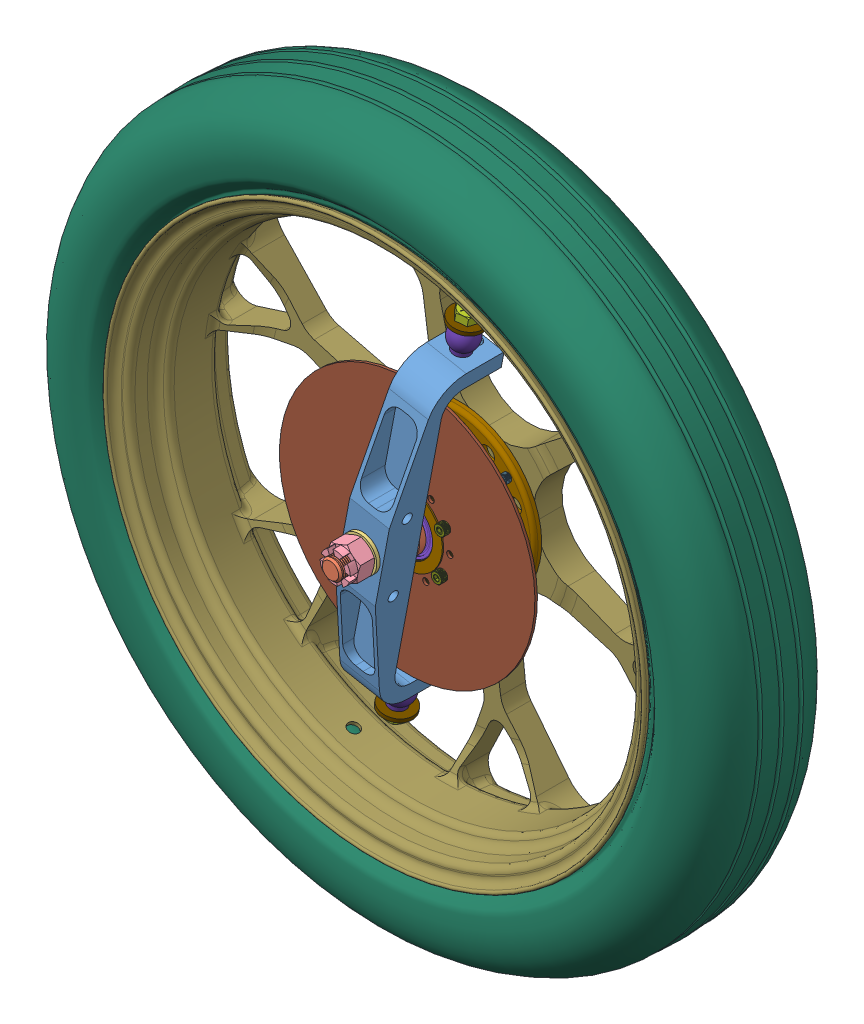
SolidWorks assembly SpindleAssy, configuration Default. Lengths in mm.
Overall size (616.2 616.2 50000).
36 component instances, 18 part files, 73 mates.
Components (placement in the parent):
- Knuckle-1: Knuckle [Default] at (82.0121 130.0239 204.0915) size (78.12 253.33 73.5)
- Spindle_Light-1: Spindle_Light [Default] at (82.0121 130.0239 204.0915) x (0 0 -1) z (0.185408 0.982662 0) size (50000 34 30)
- M16 98688A121_General Purpose Zinc-Plated Steel Washer-1: M16 98688A121_General Purpose Zinc-Plated Steel Washer [98688A121] at (82.0121 130.0239 232.5915) x (0.99983 -0.018445 0) z (0 0 1) size (28 28 2.7)
- M16x1-5 93760A128_Steel Locknut for Use with Cotter Pins-1: M16x1-5 93760A128_Steel Locknut for Use with Cotter Pins [93760A128] at (82.0121 130.0239 254.2915) x (0.982886 -0.184217 0) z (0 0 1) size (24 27.71 19.76)
- M14 98689A119_General Purpose 18-8 Stainless Steel Washer-1: M14 98689A119_General Purpose 18-8 Stainless Steel Washer [98689A119] at (82.0121 130.0239 138.2415) size (24 24 2.7)
- M14x1-5 93760A127_Steel Locknut for Use with Cotter Pins-1: M14x1-5 93760A127_Steel Locknut for Use with Cotter Pins [93760A127] at (82.0121 130.0239 120.8915) x (-0.661913 -0.74958 0) z (0 0 -1) size (22 25.4 16.76)
- 91257A659_Zinc Yellow-Chromate Plated Hex Head Screw-2: 91257A659_Zinc Yellow-Chromate Plated Hex Head Screw [91257A659] at (58.1191 3.3909 177.4439) x (0.185408 0.982662 0) z (0.110595 -0.020867 0.993646) size (57.6 16.5 14.29)
- 91257A659_Zinc Yellow-Chromate Plated Hex Head Screw-3: 91257A659_Zinc Yellow-Chromate Plated Hex Head Screw [91257A659] at (105.9051 256.6568 177.4439) x (-0.185408 -0.982662 0) z (-0.685297 0.129301 0.716693) size (57.6 16.5 14.29)
- SKF_6004-2Z.stp-1: SKF_6004-2Z.stp [Default] at (82.0121 130.0239 185.0915) x (0 0 1) z (-0.58163 0.813454 0) size (12 42 42)
- Hub5-16-1: Hub5-16 [Default] at (82.0121 130.0239 173.6746) x (-0.944813 0.32761 0) z (0.32761 0.944813 0) size (130 85 130)
- SKF_6003-2Z.stp-1: SKF_6003-2Z.stp [Default] at (82.0121 130.0239 149.5915) x (0 0 -1) z (0.973183 -0.230032 0) size (10 35 35)
- BasicBrakeDisc-1: BasicBrakeDisc [Default] at (82.0121 130.0239 195.0915) x (0.071911 0.997411 0) z (0 0 1) size (190.5 190.5 3.17)
- rimmachined v13.2-1: rimmachined v13.2 [Default] at (82.0121 130.0239 177.3915) x (0 0 -1) z (-0.981935 -0.189217 0) size (93.59 431.57 431.57)
- 92415A381_Zinc-Plated Steel Unthreaded Spacer-2: 92415A381_Zinc-Plated Steel Unthreaded Spacer [92415A381] at (71.0682 186.982 155.2387) size (7.94 7.94 7.21)
- 92415A381_Zinc-Plated Steel Unthreaded Spacer-3: 92415A381_Zinc-Plated Steel Unthreaded Spacer [92415A381] at (27.2129 149.0252 155.2387) size (7.94 7.94 7.21)
- 92415A381_Zinc-Plated Steel Unthreaded Spacer-4: 92415A381_Zinc-Plated Steel Unthreaded Spacer [92415A381] at (38.1569 92.0671 155.2387) size (7.94 7.94 7.21)
- 92415A381_Zinc-Plated Steel Unthreaded Spacer-5: 92415A381_Zinc-Plated Steel Unthreaded Spacer [92415A381] at (92.956 73.0657 155.2387) size (7.94 7.94 7.21)
- 92415A381_Zinc-Plated Steel Unthreaded Spacer-6: 92415A381_Zinc-Plated Steel Unthreaded Spacer [92415A381] at (136.8113 111.0225 155.2387) size (7.94 7.94 7.21)
- 92415A381_Zinc-Plated Steel Unthreaded Spacer-7: 92415A381_Zinc-Plated Steel Unthreaded Spacer [92415A381] at (125.8674 167.9807 155.2387) size (7.94 7.94 7.21)
- 8-32x3-8 92196A192_18-8 Stainless Steel Socket Head Screw-1: 8-32x3-8 92196A192_18-8 Stainless Steel Socket Head Screw [92196A192] at (92.956 73.0657 158.4118) size (6.85 6.85 14.15)
- 8-32x3-8 92196A192_18-8 Stainless Steel Socket Head Screw-2: 8-32x3-8 92196A192_18-8 Stainless Steel Socket Head Screw [92196A192] at (38.1569 92.0671 158.4118) size (6.85 6.85 14.15)
- 8-32x3-8 92196A192_18-8 Stainless Steel Socket Head Screw-3: 8-32x3-8 92196A192_18-8 Stainless Steel Socket Head Screw [92196A192] at (136.8113 111.0225 158.4118) size (6.85 6.85 14.15)
- 8-32x3-8 92196A192_18-8 Stainless Steel Socket Head Screw-4: 8-32x3-8 92196A192_18-8 Stainless Steel Socket Head Screw [92196A192] at (125.8674 167.9807 158.4118) size (6.85 6.85 14.15)
- 8-32x3-8 92196A192_18-8 Stainless Steel Socket Head Screw-5: 8-32x3-8 92196A192_18-8 Stainless Steel Socket Head Screw [92196A192] at (71.0682 186.982 158.4118) size (6.85 6.85 14.15)
- 8-32x3-8 92196A192_18-8 Stainless Steel Socket Head Screw-6: 8-32x3-8 92196A192_18-8 Stainless Steel Socket Head Screw [92196A192] at (27.2129 149.0252 158.4118) size (6.85 6.85 14.15)
- Michelin Tire-1: Michelin Tire [Default] at (82.0121 130.0239 177.3915) x (0 0 1) z (-0.993534 -0.113534 0) size (101.13 556.61 556.61)
- M5x10 91290A224_Alloy Steel Socket Head Screw-1: M5x10 91290A224_Alloy Steel Socket Head Screw [91290A224] at (84.4571 163.9358 194.5915) x (0.901899 0.431946 0) z (0 0 1) size (8.5 8.5 15.31)
- M5x10 91290A224_Alloy Steel Socket Head Screw-2: M5x10 91290A224_Alloy Steel Socket Head Screw [91290A224] at (53.866 149.0973 194.5915) x (-0.609316 -0.792927 0) z (0 0 1) size (8.5 8.5 15.31)
- M5x10 91290A224_Alloy Steel Socket Head Screw-3: M5x10 91290A224_Alloy Steel Socket Head Screw [91290A224] at (112.6032 144.8625 194.5915) x (0.740699 0.671837 0) z (0 0 1) size (8.5 8.5 15.31)
- M5x10 91290A224_Alloy Steel Socket Head Screw-4: M5x10 91290A224_Alloy Steel Socket Head Screw [91290A224] at (110.1583 110.9505 194.5915) x (-0.161403 -0.986889 0) z (0 0 1) size (8.5 8.5 15.31)
- M5x10 91290A224_Alloy Steel Socket Head Screw-5: M5x10 91290A224_Alloy Steel Socket Head Screw [91290A224] at (51.421 115.1853 194.5915) x (0.079005 -0.996874 0) z (0 0 1) size (8.5 8.5 15.31)
- M5x10 91290A224_Alloy Steel Socket Head Screw-6: M5x10 91290A224_Alloy Steel Socket Head Screw [91290A224] at (79.5671 96.1119 194.5915) x (-0.159143 -0.987256 0) z (0 0 1) size (8.5 8.5 15.31)
- BallSuper-Swivel  Joint Rod End6960T231_-1: BallSuper-Swivel  Joint Rod End6960T231_ [6960T231] at (75.3125 -8.1245 178.3098) x (-0.044663 0.008427 0.998967) z (-0.185408 -0.982662 0) size (20.64 20.64 22.23)
- BallSuper-Swivel  Joint Rod End6960T231_-2: BallSuper-Swivel  Joint Rod End6960T231_ [6960T231] at (109.0836 264.3285 196.4178) x (0.978736 -0.184667 -0.089292) z (0.185408 0.982662 0) size (20.64 20.64 22.23)
- 3-8 98029A046_Black-Oxide Steel Oversized Washer-1: 3-8 98029A046_Black-Oxide Steel Oversized Washer [98029A046] at (54.2751 -16.9823 177.4439) x (0.965511 -0.182172 -0.186017) z (0.185408 0.982662 0) size (25.4 25.4 2.98)
- 3-8 98029A046_Black-Oxide Steel Oversized Washer-2: 3-8 98029A046_Black-Oxide Steel Oversized Washer [98029A046] at (109.7491 277.0301 177.4439) x (0.965511 -0.182172 -0.186017) z (0.185408 0.982662 0) size (25.4 25.4 2.98)
Mates (geometry in assembly coordinates):
- Coincident1: coincident anti-aligned: circle of Knuckle-1; circle of Spindle_Light-1
- Concentric1: concentric aligned: circle of Knuckle-1; circle of M16 98688A121_General Purpose Zinc-Plated Steel Washer-1
- Concentric2: concentric aligned: circle of M16 98688A121_General Purpose Zinc-Plated Steel Washer-1; circle of M16x1-5 93760A128_Steel Locknut for Use with Cotter Pins-1
- Coincident2: coincident anti-aligned: plane of Knuckle-1 through (82.0121 130.0239 232.5915) normal (0 0 1); plane of M16 98688A121_General Purpose Zinc-Plated Steel Washer-1 through (82.0121 130.0239 232.5915) normal (0 0 -1)
- Coincident3: coincident anti-aligned: plane of M16 98688A121_General Purpose Zinc-Plated Steel Washer-1 through (82.0121 130.0239 235.2915) normal (0 0 1); plane of M16x1-5 93760A128_Steel Locknut for Use with Cotter Pins-1 through (84.5647 143.6431 235.2915) normal (0 0 -1)
- Parallel1: parallel aligned: plane of Spindle_Light-1 through (82.0121 130.0239 258.0915) normal (0 0 1); plane of M16x1-5 93760A128_Steel Locknut for Use with Cotter Pins-1 through (82.0121 130.0239 248.2915) normal (0 0 1)
- Concentric3: concentric anti-aligned: circle of M14 98689A119_General Purpose 18-8 Stainless Steel Washer-1; circle of M14x1-5 93760A127_Steel Locknut for Use with Cotter Pins-1
- Coincident5: coincident anti-aligned: plane of M14 98689A119_General Purpose 18-8 Stainless Steel Washer-1 through (82.0121 130.0239 136.8915) normal (0 0 -1); plane of M14x1-5 93760A127_Steel Locknut for Use with Cotter Pins-1 through (75.0117 150.8804 136.8915) normal (0 0 1)
- Concentric4: concentric anti-aligned: circle of Spindle_Light-1; circle of M14 98689A119_General Purpose 18-8 Stainless Steel Washer-1
- Perpendicular1: perpendicular: line of Knuckle-1 through (84.6232 230.1587 204.0915) axis (-0.185408 -0.982662 0); line of Spindle_Light-1 through (76.9319 146.2471 204.0915) axis (0.982662 -0.185408 0)
- Concentric5: concentric aligned: circle of Knuckle-1; circle of Super-Swivel Ball Joint Ball End2-1
- Coincident7: coincident anti-aligned: plane of Knuckle-1 through (89.6292 256.6906 232.5915) normal (0.185408 0.982662 0); plane of Super-Swivel Ball Joint Ball End2-1 through (107.5018 254.0508 172.0915) normal (-0.20131 -0.979528 0)
- Concentric6: concentric anti-aligned: circle of Knuckle-1; circle of Super-Swivel Ball Joint Ball End2-2
- Coincident8: coincident anti-aligned: plane of Knuckle-1 through (74.395 3.3572 232.5915) normal (-0.185408 -0.982662 0); plane of Super-Swivel Ball Joint Ball End2-2 through (56.5224 5.997 172.0915) normal (0.20131 0.979528 0)
- Coincident11: coincident anti-aligned: circle of Knuckle-1; circle of SteerArm-1
- Coincident12: coincident anti-aligned: circle of Knuckle-1; circle of SteerArm-1
- Concentric7: concentric anti-aligned: circle of Spindle_Light-1; circle of SKF_6004-2Z.stp-1
- Coincident13: coincident anti-aligned: plane of Spindle_Light-1 through (70.2202 132.2488 197.0915) normal (0 0 -1); plane of SKF_6004-2Z.stp-1 through (90.6347 136.1891 197.0915) normal (0 0 1)
- Coincident14: coincident anti-aligned: plane of SKF_6004-2Z.stp-1 through (98.6066 141.8891 185.0915) normal (0 0 -1); plane of Hub5-16-1 through (64.0607 136.2485 185.0915) normal (0 0 1)
- Concentric8: concentric aligned: cylinder of SKF_6004-2Z.stp-1 through (82.0121 130.0239 235.0915) axis (0 0 1) radius 21; cylinder of Hub5-16-1 through (82.0121 130.0239 1099.7023) axis (0 0 1) radius 21
- Concentric9: concentric anti-aligned: cylinder of Hub5-16-1 through (82.0121 130.0239 1099.7023) axis (0 0 1) radius 17.5; cylinder of SKF_6003-2Z.stp-1 through (82.0121 130.0239 99.5915) axis (0 0 -1) radius 17.5
- Coincident15: coincident anti-aligned: plane of Hub5-16-1 through (67.3675 135.1018 149.5915) normal (0 0 -1); plane of SKF_6003-2Z.stp-1 through (85.9687 146.7626 149.5915) normal (0 0 1)
- Coincident16: coincident anti-aligned: plane of M14 98689A119_General Purpose 18-8 Stainless Steel Washer-1 through (82.0121 130.0239 139.5915) normal (0 0 1); plane of SKF_6003-2Z.stp-1 through (84.0364 138.5879 139.5915) normal (0 0 -1)
- Concentric10: concentric aligned: circle of Hub5-16-1; circle of BasicBrakeDisc-1
- Coincident18: coincident anti-aligned: plane of Hub5-16-1 through (54.6125 139.5246 195.0915) normal (0 0 1); plane of BasicBrakeDisc-1 through (82.0121 130.0239 195.0915) normal (0 0 -1)
- Concentric11: concentric anti-aligned: cylinder of Hub5-16-1 through (82.0121 130.0239 1099.7023) axis (0 0 1) radius 47; cylinder of rimmachined v13.2-1 through (82.0121 130.0239 168.2915) axis (0 0 -1) radius 47.005
- Coincident19: coincident aligned: circle of Hub5-16-1; circle of 92415A381_Zinc-Plated Steel Unthreaded Spacer-5
- Coincident20: coincident aligned: circle of Hub5-16-1; circle of 92415A381_Zinc-Plated Steel Unthreaded Spacer-4
- Coincident21: coincident aligned: circle of Hub5-16-1; circle of 92415A381_Zinc-Plated Steel Unthreaded Spacer-3
- Coincident22: coincident aligned: circle of Hub5-16-1; circle of 92415A381_Zinc-Plated Steel Unthreaded Spacer-2
- Coincident23: coincident aligned: circle of Hub5-16-1; circle of 92415A381_Zinc-Plated Steel Unthreaded Spacer-7
- Coincident24: coincident aligned: circle of Hub5-16-1; circle of 92415A381_Zinc-Plated Steel Unthreaded Spacer-6
- Concentric121: concentric anti-aligned: cylinder of Hub5-16-1 through (92.956 73.0657 151.0915) axis (0 0 1) radius 2.15; cylinder of 8-32x3-8 92196A192_18-8 Stainless Steel Socket Head Screw-1 through (92.956 73.0657 151.5665) axis (0 0 -1) radius 2.0828
- Coincident251: coincident anti-aligned: plane of Hub5-16-1 through (23.4337 150.3357 161.0915) normal (0 0 1); plane of 8-32x3-8 92196A192_18-8 Stainless Steel Socket Head Screw-1 through (89.6985 73.0657 161.0915) normal (0 0 -1)
- Concentric131: concentric anti-aligned: cylinder of Hub5-16-1 through (38.1569 92.0671 151.0915) axis (0 0 1) radius 2.15; cylinder of 8-32x3-8 92196A192_18-8 Stainless Steel Socket Head Screw-2 through (38.1569 92.0671 151.5665) axis (0 0 -1) radius 2.0828
- Coincident261: coincident anti-aligned: plane of Hub5-16-1 through (23.4337 150.3357 161.0915) normal (0 0 1); plane of 8-32x3-8 92196A192_18-8 Stainless Steel Socket Head Screw-2 through (34.8993 92.0671 161.0915) normal (0 0 -1)
- Concentric141: concentric anti-aligned: cylinder of Hub5-16-1 through (136.8113 111.0225 151.0915) axis (0 0 1) radius 2.15; cylinder of 8-32x3-8 92196A192_18-8 Stainless Steel Socket Head Screw-3 through (136.8113 111.0225 151.5665) axis (0 0 -1) radius 2.0828
- Coincident271: coincident anti-aligned: plane of Hub5-16-1 through (23.4337 150.3357 161.0915) normal (0 0 1); plane of 8-32x3-8 92196A192_18-8 Stainless Steel Socket Head Screw-3 through (133.5537 111.0225 161.0915) normal (0 0 -1)
- Concentric151: concentric anti-aligned: cylinder of Hub5-16-1 through (125.8674 167.9807 151.0915) axis (0 0 1) radius 2.15; cylinder of 8-32x3-8 92196A192_18-8 Stainless Steel Socket Head Screw-4 through (125.8674 167.9807 151.5665) axis (0 0 -1) radius 2.0828
- Coincident281: coincident anti-aligned: plane of Hub5-16-1 through (23.4337 150.3357 161.0915) normal (0 0 1); plane of 8-32x3-8 92196A192_18-8 Stainless Steel Socket Head Screw-4 through (122.6098 167.9807 161.0915) normal (0 0 -1)
- Concentric161: concentric anti-aligned: cylinder of Hub5-16-1 through (71.0682 186.982 151.0915) axis (0 0 1) radius 2.15; cylinder of 8-32x3-8 92196A192_18-8 Stainless Steel Socket Head Screw-5 through (71.0682 186.982 151.5665) axis (0 0 -1) radius 2.0828
- Coincident291: coincident anti-aligned: plane of Hub5-16-1 through (23.4337 150.3357 161.0915) normal (0 0 1); plane of 8-32x3-8 92196A192_18-8 Stainless Steel Socket Head Screw-5 through (67.8106 186.982 161.0915) normal (0 0 -1)
- Concentric171: concentric anti-aligned: cylinder of Hub5-16-1 through (27.2129 149.0252 151.0915) axis (0 0 1) radius 2.15; cylinder of 8-32x3-8 92196A192_18-8 Stainless Steel Socket Head Screw-6 through (27.2129 149.0252 151.5665) axis (0 0 -1) radius 2.0828
- Coincident301: coincident anti-aligned: plane of Hub5-16-1 through (23.4337 150.3357 161.0915) normal (0 0 1); plane of 8-32x3-8 92196A192_18-8 Stainless Steel Socket Head Screw-6 through (23.9554 149.0252 161.0915) normal (0 0 -1)
- Tangent1: tangent anti-aligned: plane of rimmachined v13.2-1 through (88.5859 74.7696 150.7915) normal (0.981935 0.189217 0); cylinder of 92415A381_Zinc-Plated Steel Unthreaded Spacer-5 through (92.956 73.0657 151.6669) axis (0 0 1) radius 3.9688
- Coincident31: coincident anti-aligned: plane of Hub5-16-1 through (37.6059 145.4215 155.0915) normal (0 0 -1); plane of rimmachined v13.2-1 through (89.5808 90.7465 155.0915) normal (0 0 1)
- Concentric18: concentric aligned: cone of rimmachined v13.2-1 through (82.0121 130.0239 200.42) axis (0 0 -1); cylinder of Michelin Tire-1 through (82.0121 130.0239 74.6686) axis (0 0 -1) radius 203
- Coincident32: coincident anti-aligned: plane of rimmachined v13.2-1 through (82.0121 130.0239 177.3915) normal (0 0 -1); plane of Michelin Tire-1 through (82.0121 130.0239 177.3915) normal (0 0 1)
- Concentric19: concentric anti-aligned: cylinder of Hub5-16-1 through (67.1735 160.615 185.0915) axis (0 0 1) radius 2; cylinder of BasicBrakeDisc-1 through (67.1735 160.615 197.0915) axis (0 0 -1) radius 2.497
- Concentric20: concentric anti-aligned: circle of BasicBrakeDisc-1; circle of M5x10 91290A224_Alloy Steel Socket Head Screw-2
- Coincident33: coincident anti-aligned: plane of BasicBrakeDisc-1 through (82.0121 130.0239 197.0915) normal (0 0 1); plane of M5x10 91290A224_Alloy Steel Socket Head Screw-2 through (56.3032 152.269 197.0915) normal (0 0 -1)
- Concentric21: concentric anti-aligned: circle of BasicBrakeDisc-1; circle of M5x10 91290A224_Alloy Steel Socket Head Screw-1
- Concentric22: concentric anti-aligned: circle of BasicBrakeDisc-1; circle of M5x10 91290A224_Alloy Steel Socket Head Screw-3
- Concentric23: concentric anti-aligned: circle of BasicBrakeDisc-1; circle of M5x10 91290A224_Alloy Steel Socket Head Screw-4
- Concentric24: concentric anti-aligned: circle of BasicBrakeDisc-1; circle of M5x10 91290A224_Alloy Steel Socket Head Screw-6
- Concentric25: concentric anti-aligned: circle of BasicBrakeDisc-1; circle of M5x10 91290A224_Alloy Steel Socket Head Screw-5
- Coincident34: coincident anti-aligned: plane of BasicBrakeDisc-1 through (82.0121 130.0239 197.0915) normal (0 0 1); plane of M5x10 91290A224_Alloy Steel Socket Head Screw-1 through (80.8495 162.2081 197.0915) normal (0 0 -1)
- Coincident36: coincident anti-aligned: plane of BasicBrakeDisc-1 through (82.0121 130.0239 197.0915) normal (0 0 1); plane of M5x10 91290A224_Alloy Steel Socket Head Screw-3 through (109.6404 142.1751 197.0915) normal (0 0 -1)
- Coincident37: coincident anti-aligned: plane of BasicBrakeDisc-1 through (82.0121 130.0239 197.0915) normal (0 0 1); plane of M5x10 91290A224_Alloy Steel Socket Head Screw-5 through (51.105 119.1728 197.0915) normal (0 0 -1)
- Coincident38: coincident anti-aligned: plane of BasicBrakeDisc-1 through (82.0121 130.0239 197.0915) normal (0 0 1); plane of M5x10 91290A224_Alloy Steel Socket Head Screw-6 through (80.2037 100.0609 197.0915) normal (0 0 -1)
- Coincident39: coincident anti-aligned: plane of BasicBrakeDisc-1 through (82.0121 130.0239 197.0915) normal (0 0 1); plane of M5x10 91290A224_Alloy Steel Socket Head Screw-4 through (110.8039 114.898 197.0915) normal (0 0 -1)
- Coincident302: coincident anti-aligned: plane of Knuckle-1 through (89.6292 256.6906 232.5915) normal (0.185408 0.982662 0); plane of BallSuper-Swivel  Joint Rod End6960T231_-2 through (105.3518 253.724 177.4439) normal (-0.185408 -0.982662 0)
- Coincident303: coincident anti-aligned: plane of Knuckle-1 through (74.395 3.3572 232.5915) normal (-0.185408 -0.982662 0); plane of BallSuper-Swivel  Joint Rod End6960T231_-1 through (58.6725 6.3237 177.4439) normal (0.185408 0.982662 0)
- Concentric174: concentric aligned: cylinder of Knuckle-1 through (57.5915 0.5946 177.4439) axis (0.185408 0.982662 0) radius 4.7625; cylinder of BallSuper-Swivel  Joint Rod End6960T231_-2 through (105.4989 254.504 177.4439) axis (0.185408 0.982662 0) radius 4.7625
- Concentric175: concentric anti-aligned: cylinder of Knuckle-1 through (57.5915 0.5946 177.4439) axis (0.185408 0.982662 0) radius 4.7625; cylinder of BallSuper-Swivel  Joint Rod End6960T231_-1 through (58.5253 5.5437 177.4439) axis (-0.185408 -0.982662 0) radius 4.7625
- Concentric176: concentric anti-aligned: cylinder of 91257A659_Zinc Yellow-Chromate Plated Hex Head Screw-2 through (53.9984 -18.4487 177.4439) axis (0.185408 0.982662 0) radius 4.7625; cylinder of BallSuper-Swivel  Joint Rod End6960T231_-1 through (58.5253 5.5437 177.4439) axis (-0.185408 -0.982662 0) radius 4.7625
- Concentric177: concentric anti-aligned: cylinder of 91257A659_Zinc Yellow-Chromate Plated Hex Head Screw-2 through (53.9984 -18.4487 177.4439) axis (0.185408 0.982662 0) radius 4.7625; cylinder of 3-8 98029A046_Black-Oxide Steel Oversized Washer-1 through (54.5518 -15.516 177.4439) axis (-0.185408 -0.982662 0) radius 5.1562
- Coincident304: coincident anti-aligned: plane of BallSuper-Swivel  Joint Rod End6960T231_-1 through (54.5518 -15.516 177.4439) normal (-0.185408 -0.982662 0); plane of 3-8 98029A046_Black-Oxide Steel Oversized Washer-1 through (54.5518 -15.516 177.4439) normal (0.185408 0.982662 0)
- Coincident305: coincident anti-aligned: plane of 91257A659_Zinc Yellow-Chromate Plated Hex Head Screw-2 through (50.7613 -17.8379 185.0065) normal (0.185408 0.982662 0); plane of 3-8 98029A046_Black-Oxide Steel Oversized Washer-1 through (53.9984 -18.4487 177.4439) normal (-0.185408 -0.982662 0)
- Concentric178: concentric aligned: circle of BallSuper-Swivel  Joint Rod End6960T231_-2; circle of 3-8 98029A046_Black-Oxide Steel Oversized Washer-2
- Coincident306: coincident anti-aligned: plane of BallSuper-Swivel  Joint Rod End6960T231_-2 through (109.4725 275.5637 177.4439) normal (0.185408 0.982662 0); plane of 3-8 98029A046_Black-Oxide Steel Oversized Washer-2 through (109.4725 275.5637 177.4439) normal (-0.185408 -0.982662 0)
- Concentric179: concentric anti-aligned: cylinder of 91257A659_Zinc Yellow-Chromate Plated Hex Head Screw-3 through (110.0258 278.4965 177.4439) axis (-0.185408 -0.982662 0) radius 4.7625; cylinder of BallSuper-Swivel  Joint Rod End6960T231_-2 through (105.4989 254.504 177.4439) axis (0.185408 0.982662 0) radius 4.7625
- Coincident307: coincident anti-aligned: plane of 91257A659_Zinc Yellow-Chromate Plated Hex Head Screw-3 through (108.0349 278.8721 185.4402) normal (-0.185408 -0.982662 0); plane of 3-8 98029A046_Black-Oxide Steel Oversized Washer-2 through (110.0258 278.4965 177.4439) normal (0.185408 0.982662 0)
